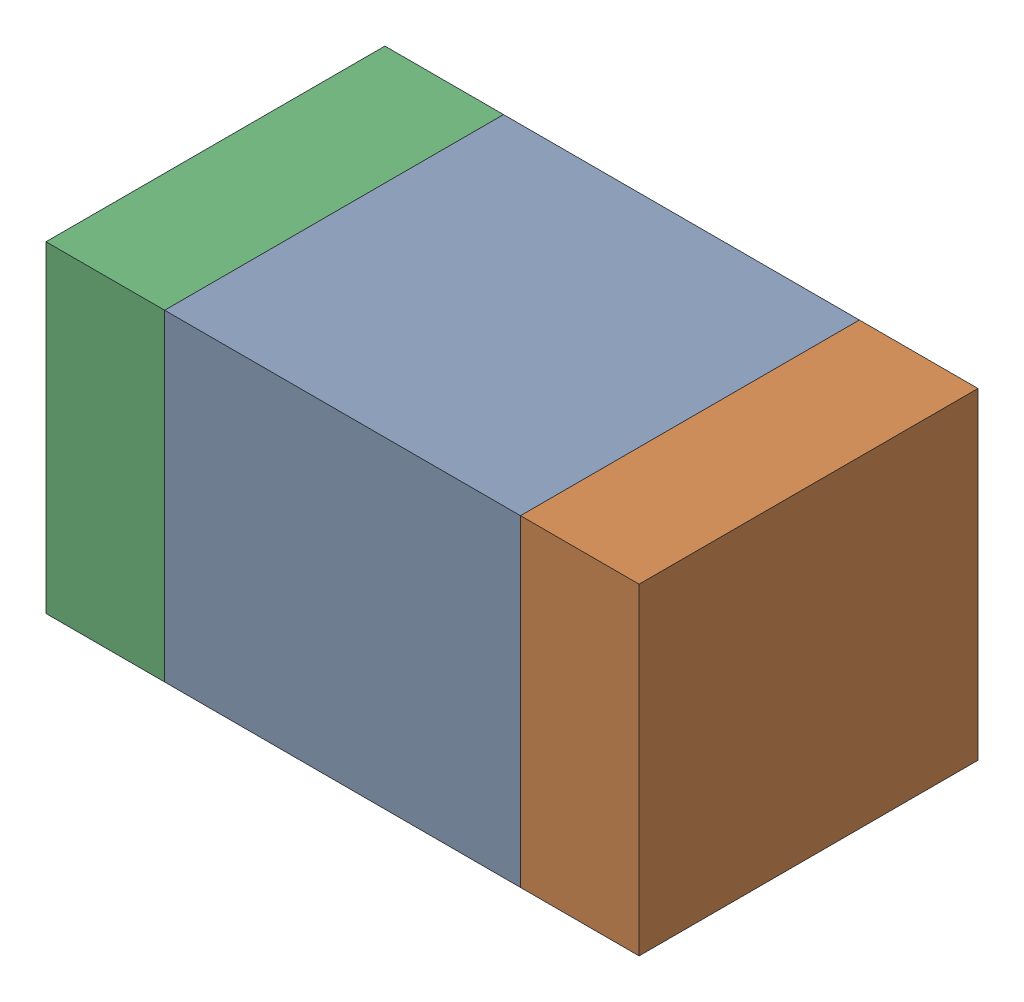
SolidWorks assembly C418PCB, configuration Default. Lengths in mm.
Overall size (1.75 0.95 1).
6 component instances, 2 part files, 0 mates.
Components (placement in the parent):
- 761616112-1: 761616112 [Default] at (120.1 89.9 -2.6638) size (1.05 0.95 1)
  - Extruded_14-1: Extruded_14 [Default] at origin size (1.05 0.95 1)
- 761616248-1: 761616248 [Default] at (120.8 89.9 -2.6638) size (0.35 0.95 1)
  - Extruded_15-1: Extruded_15 [Default] at origin size (0.35 0.95 1)
- 761616248-2: 761616248 [Default] at (119.4 89.9 -2.6638) size (0.35 0.95 1)
  - Extruded_15-1: Extruded_15 [Default] at origin size (0.35 0.95 1)
